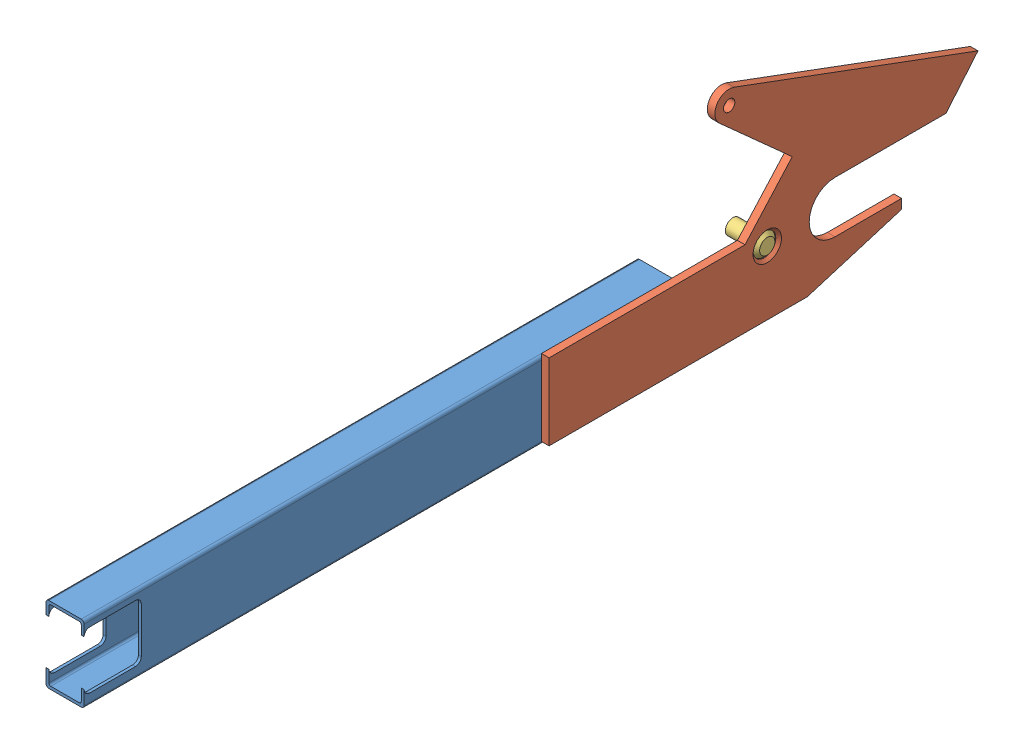
SolidWorks assembly ТП.016.10.01.01.02.00 - Боковина рампы с вилкой, configuration Правая. Lengths in mm.
Overall size (24 116.43 465.09).
4 component instances, 3 part files, 4 mates.
Components (placement in the parent):
- ТП.016.10.01.01.02.01 - Боковина рампы-1: ТП.016.10.01.01.02.01 - Боковина рампы [--] at origin size (20 40 310)
- ТП.016.10.01.01.02.02.00 - Вилка замка-1: ТП.016.10.01.01.02.02.00 - Вилка замка [Правая] at (4 35 -360) x (0 0 1) z (-1 0 0) size (225.09 114.93 18)
  - ТП.016.10.01.01.02.02.01 - Вилка навески (Ст3 S4мм)-1: ТП.016.10.01.01.02.02.01 - Вилка навески (Ст3 S4мм) [Правая] at origin size (225.09 114.93 4)
  - ТП.016.10.01.01.02.02.02 - Ось вилки навески-1: ТП.016.10.01.01.02.02.02 - Ось вилки навески [--] at (35.5 0 0) x (0.984194 0.177092 0) z (0 0 1) size (12 12 18)
Mates (geometry in assembly coordinates):
- Совпадение1: coincident: plane of ТП.016.10.01.01.02.01 - Боковина рампы-1 through (0 38.5 -394.7214) normal (1 0 0); plane of ТП.016.10.01.01.02.02.00 - Вилка замка-1/ТП.016.10.01.01.02.02.01 - Вилка навески (Ст3 S4мм)-1 through (0 108.9349 -304.5) normal (-1 0 0)
- Совпадение2: coincident: plane of ТП.016.10.01.01.02.01 - Боковина рампы-1 through (-17.5 1.5 -394.7214) normal (0 1 0); plane of ТП.016.10.01.01.02.02.00 - Вилка замка-1/ТП.016.10.01.01.02.02.01 - Вилка навески (Ст3 S4мм)-1 through (0 1.5 -210) normal (0 -1 0)
- Расстояние1: distance = 70 mm: plane of ТП.016.10.01.01.02.01 - Боковина рампы-1 through (-12 41.5 -280) normal (0 0 -1); plane of ТП.016.10.01.01.02.02.00 - Вилка замка-1/ТП.016.10.01.01.02.02.01 - Вилка навески (Ст3 S4мм)-1 through (0 41.5 -210) normal (0 0 1)
- Совпадение3: coincident: plane of ТП.016.10.01.01.02.01 - Боковина рампы-1 through (-20 38.5 -534.7214) normal (-1 0 0); plane of ТП.016.10.01.01.02.02.00 - Вилка замка-1/ТП.016.10.01.01.02.02.01 - Вилка навески (Ст3 S4мм)-1 through (-20 108.3125 -444.5) normal (1 0 0)
